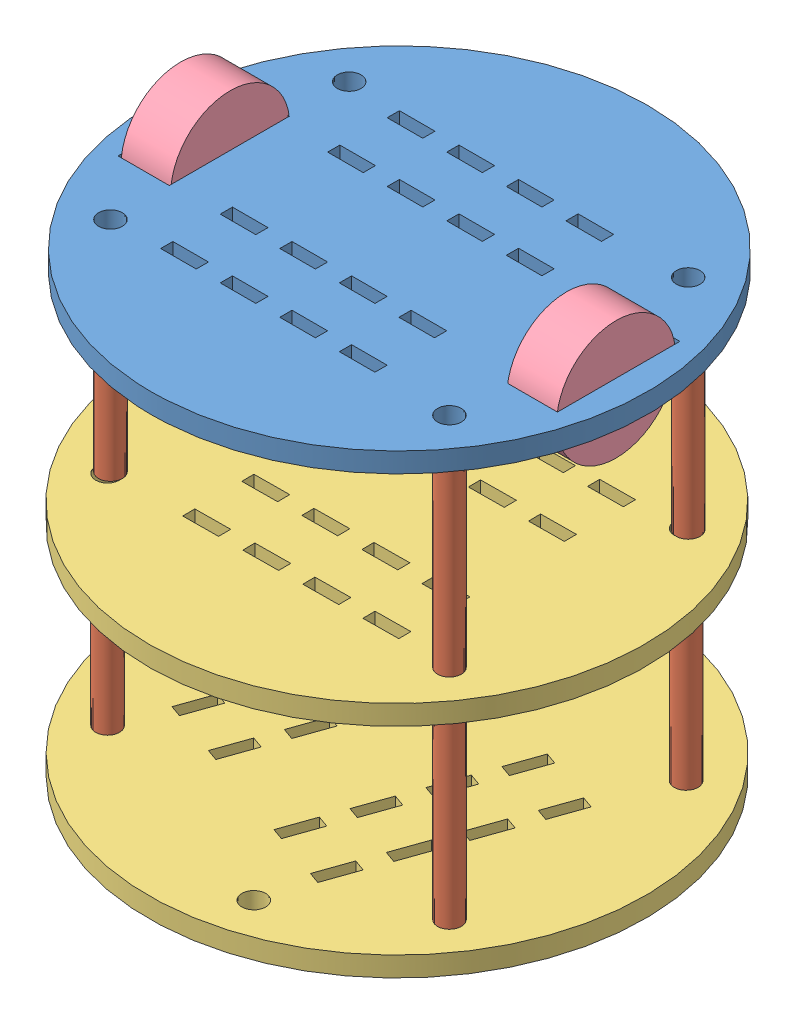
SolidWorks assembly Assem1, configuration Default. Lengths in mm.
Overall size (455.17 255.22 417.25).
13 component instances, 4 part files, 14 mates.
Components (placement in the parent):
- base-1: base [Default] at (130.2868 203.4212 293.3609) size (309.07 10 373.72)
- rod-1: rod [Default] at (44.9183 103.4212 353.4821) size (12 100 12)
- rod-2: rod [Default] at (215.6553 103.4212 233.2396) size (12 100 12)
- rod-3: rod [Default] at (44.9183 103.4212 233.2396) size (12 100 12)
- rod-4: rod [Default] at (215.6553 103.4212 353.4821) size (12 100 12)
- floors-1: floors [Default] at (129.7792 93.4212 294.0882) x (-0.999964 0 0.008494) z (-0.008494 0 -0.999964) size (309.07 10 373.72)
- wheel-1: wheel [Default] at (44.1001 208.6416 292.3369) x (0 1 0) z (0 0 1) size (60 25 60)
- wheel-2: wheel [Default] at (241.4735 208.5703 295.3633) x (0 1 0) z (0 0 1) size (60 25 60)
- rod-5: rod [Default] at (215.6553 93.4212 353.4821) x (-0.837169 0 -0.546944) z (-0.546944 0 0.837169) size (12 100 12)
- rod-6: rod [Default] at (214.634 93.4212 233.244) x (-0.837169 0 -0.546944) z (-0.546944 0 0.837169) size (12 100 12)
- rod-7: rod [Default] at (43.9031 -6.5788 234.6942) size (12 100 12)
- rod-8: rod [Default] at (44.9245 -6.5788 354.9323) size (12 100 12)
- floors-2: floors [Default] at (129.5669 -6.5788 293.7909) x (0.332213 0 -0.943204) z (-0.943204 0 -0.332213) size (309.07 10 373.72)
Mates (geometry in assembly coordinates):
- Coincident1: coincident aligned: circle of base-1; circle of rod-1
- Coincident2: coincident anti-aligned: circle of base-1; circle of rod-3
- Coincident3: coincident anti-aligned: circle of base-1; circle of rod-4
- Coincident4: coincident aligned: circle of base-1; circle of rod-2
- Coincident10: coincident aligned: circle of rod-4; circle of floors-1
- Coincident14: coincident anti-aligned: plane of base-1 through (19.1001 213.4212 263.2396) normal (1 0 0); plane of wheel-1 through (19.1001 208.6416 292.3369) normal (-1 0 0)
- Parallel3: parallel anti-aligned: plane of base-1 through (44.9183 213.4212 293.3609) normal (-1 0 0); plane of wheel-1 through (44.1001 208.6416 292.3369) normal (1 0 0)
- Coincident16: coincident anti-aligned: plane of base-1 through (241.4735 213.4212 263.2396) normal (-1 0 0); plane of wheel-2 through (241.4735 208.5703 295.3633) normal (1 0 0)
- Parallel4: parallel anti-aligned: plane of base-1 through (215.6553 213.4212 293.3609) normal (1 0 0); plane of wheel-2 through (216.4735 208.5703 295.3633) normal (-1 0 0)
- Coincident20: coincident anti-aligned: circle of floors-1; circle of rod-5
- Coincident21: coincident anti-aligned: circle of floors-1; circle of rod-6
- Coincident22: coincident aligned: circle of floors-1; circle of rod-7
- Coincident23: coincident aligned: circle of floors-1; circle of rod-8
- Coincident28: coincident aligned: circle of rod-6; circle of floors-2
